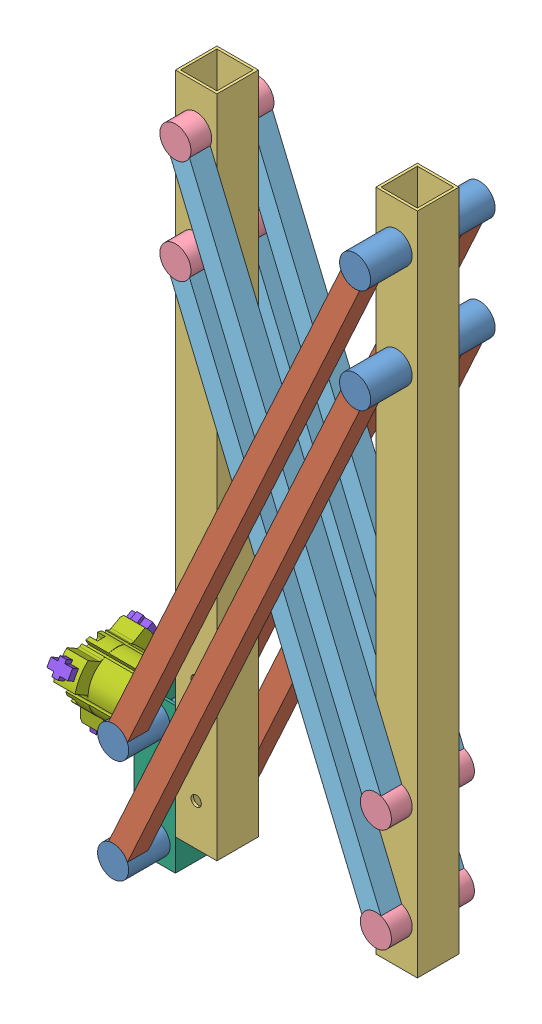
SolidWorks assembly Arm Assembly, configuration Down. Lengths in mm.
Overall size (424.42 852.13 156.64).
24 component instances, 8 part files, 47 mates.
Components (placement in the parent):
- End Long-1: End Long [Default] at (270.7162 -334.2521 -37.7204) x (-0.353555 0.935414 0) z (0 0 1)
- Link Long-1: Link Long [Default] at (-13.8532 -986.1623 13.0796) x (0.416361 0.909199 0) z (0.909199 -0.416361 0)
- Link Long-2: Link Long [Default] at (-13.8532 -986.1623 -113.9204) x (0.416361 0.909199 0) z (0.909199 -0.416361 0)
- End Long-2: End Long [Default] at (-25.4 -980.8746 -37.7204) x (0.851709 -0.524015 0) z (0 0 1)
- End Long-3: End Long [Default] at (-25.4 -853.8746 -37.7204) x (-0.966098 0.258174 0) z (0 0 1)
- Link Long-3: Link Long [Default] at (-13.8532 -859.1623 13.0796) x (0.416361 0.909199 0) z (0.909199 -0.416361 0)
- Link Long-4: Link Long [Default] at (-13.8532 -859.1623 -113.9204) x (0.416361 0.909199 0) z (0.909199 -0.416361 0)
- End Long-4: End Long [Default] at (270.7162 -207.2521 -37.7204) x (0.945044 0.326943 0) z (0 0 1)
- Post-2: Post [Default] at (270.7162 -156.4521 -37.7204) x (0 0 -1) z (-1 0 0)
- End Short-1: End Short [Default] at (25.4 -332.7517 -37.7204) x (0.945044 0.326943 0) z (0 0 1)
- End Short-2: End Short [Default] at (270.7162 -918.4521 -37.7204) x (0.945044 0.326943 0) z (0 0 1)
- Link Short-1: Link Short [Default] at (13.686 -337.658 -88.5204) x (0.386325 -0.922363 0) z (-0.922363 -0.386325 0)
- Link Short-2: Link Short [Default] at (13.686 -337.658 -12.3204) x (0.386325 -0.922363 0) z (-0.922363 -0.386325 0)
- Link Short-3: Link Short [Default] at (13.686 -210.658 -12.3204) x (0.386325 -0.922363 0) z (-0.922363 -0.386325 0)
- Link Short-4: Link Short [Default] at (13.686 -210.658 -88.5204) x (0.386325 -0.922363 0) z (-0.922363 -0.386325 0)
- End Short-3: End Short [Default] at (270.7162 -791.4521 -37.7204) x (0.945044 0.326943 0) z (0 0 1)
- End Short-4: End Short [Default] at (25.4 -205.7517 -37.7204) x (0.945044 0.326943 0) z (0 0 1)
- Post-4: Post [Default] at (25.4 -967.7517 -37.7204) x (0 0 -1) z (1 0 0)
- Post Short-1: Post Short [Default] at (-25.4 -1006.2746 -37.7204) x (0 0 -1) z (1 0 0)
- MHSL3-50D-1: MHSL3-50D [MHSL3-50D] at (-50.8 -863.4746 -37.7204) x (-1 0 0) z (0 -0.866025 0.5) size (77.5 98.66 113.92)
  - MHSL3-50D_MHSL-Body-1: MHSL3-50D_MHSL-Body [50] x (-1 0 0) z (0 0 -1) size (74.5 90.6 101.7)
  - MHSL3-50D_MHSL-Finger-1: MHSL3-50D_MHSL-Finger [50] at (61 -48 0) x (-1 0 0) z (0 0 1) size (26.2 24 20)
  - MHSL3-50D_MHSL-Finger-2: MHSL3-50D_MHSL-Finger [50] at (61 24 41.5692) x (-1 0 0) z (0 0.866025 -0.5) size (26.2 24 20)
  - MHSL3-50D_MHSL-Finger-3: MHSL3-50D_MHSL-Finger [50] at (61 24 -41.5692) x (-1 0 0) z (0 -0.866025 -0.5) size (26.2 24 20)
Mates (geometry in assembly coordinates):
- Concentric1: concentric anti-aligned: cylinder of End Long-1 through (270.7162 -334.2521 -113.9204) axis (0 0 -1) radius 19.05; cylinder of Link Long-1 through (270.7162 -334.2521 13.0796) axis (0 0 1) radius 19.05
- Coincident1: coincident aligned: plane of End Long-1 through (270.7162 -334.2521 38.4796) normal (0 0 1); plane of Link Long-1 through (282.2631 -339.5399 38.4796) normal (0 0 1)
- Concentric2: concentric anti-aligned: cylinder of End Long-1 through (270.7162 -334.2521 -113.9204) axis (0 0 -1) radius 19.05; cylinder of Link Long-2 through (270.7162 -334.2521 -113.9204) axis (0 0 1) radius 19.05
- Coincident2: coincident aligned: plane of End Long-1 through (252.8966 -340.9873 -113.9204) normal (0 0 -1); plane of Link Long-2 through (282.2631 -339.5399 -113.9204) normal (0 0 -1)
- Concentric3: concentric anti-aligned: cylinder of Link Long-1 through (-25.4 -980.8746 13.0796) axis (0 0 1) radius 19.05; cylinder of End Long-2 through (-25.4 -980.8746 -113.9204) axis (0 0 -1) radius 19.05
- Coincident3: coincident aligned: plane of Link Long-1 through (282.2631 -339.5399 38.4796) normal (0 0 1); plane of End Long-2 through (-25.4 -980.8746 38.4796) normal (0 0 1)
- Concentric4: concentric anti-aligned: cylinder of Link Long-4 through (270.7162 -207.2521 -113.9204) axis (0 0 1) radius 19.05; cylinder of End Long-4 through (270.7162 -207.2521 -113.9204) axis (0 0 -1) radius 19.05
- Concentric5: concentric anti-aligned: cylinder of End Long-3 through (-25.4 -853.8746 -113.9204) axis (0 0 -1) radius 19.05; cylinder of Link Long-3 through (-25.4 -853.8746 13.0796) axis (0 0 1) radius 19.05
- Concentric6: concentric anti-aligned: cylinder of Link Long-3 through (270.7162 -207.2521 13.0796) axis (0 0 1) radius 19.05; cylinder of End Long-4 through (270.7162 -207.2521 -113.9204) axis (0 0 -1) radius 19.05
- Coincident4: coincident aligned: plane of End Long-3 through (-25.4 -853.8746 38.4796) normal (0 0 1); plane of Link Long-3 through (282.2631 -212.5399 38.4796) normal (0 0 1)
- Coincident5: coincident aligned: plane of Link Long-4 through (282.2631 -212.5399 -113.9204) normal (0 0 -1); plane of End Long-4 through (264.488 -189.249 -113.9204) normal (0 0 -1)
- Coincident6: coincident aligned: plane of Link Long-3 through (282.2631 -212.5399 38.4796) normal (0 0 1); plane of End Long-4 through (270.7162 -207.2521 38.4796) normal (0 0 1)
- Concentric7: concentric anti-aligned: cylinder of End Long-1 through (270.7162 -334.2521 -113.9204) axis (0 0 -1) radius 6.35; circle of Post-2
- Concentric8: concentric anti-aligned: cylinder of End Long-4 through (270.7162 -207.2521 -113.9204) axis (0 0 -1) radius 6.35; circle of Post-2
- Coincident9: coincident aligned: plane of Link Long-1 through (282.2631 -339.5399 38.4796) normal (0 0 1); plane of Link Long-3 through (282.2631 -212.5399 38.4796) normal (0 0 1)
- Distance1: distance = 50.8 mm aligned: plane of End Long-4 through (270.7162 -207.2521 38.4796) normal (0 0 1); plane of Post-2 through (296.1162 -969.2521 -12.3204) normal (0 0 1)
- Concentric9: concentric anti-aligned: cylinder of Link Long-2 through (-25.4 -980.8746 -113.9204) axis (0 0 1) radius 19.05; cylinder of End Long-2 through (-25.4 -980.8746 -113.9204) axis (0 0 -1) radius 19.05
- Concentric10: concentric anti-aligned: cylinder of End Long-3 through (-25.4 -853.8746 -113.9204) axis (0 0 -1) radius 19.05; cylinder of Link Long-4 through (-25.4 -853.8746 -113.9204) axis (0 0 1) radius 19.05
- Concentric11: concentric anti-aligned: cylinder of End Short-2 through (270.7162 -918.4521 -88.5204) axis (0 0 -1) radius 19.05; cylinder of Link Short-2 through (270.7162 -918.4521 -12.3204) axis (0 0 1) radius 19.05
- Coincident11: coincident aligned: plane of End Short-2 through (270.7162 -918.4521 13.0796) normal (0 0 1); plane of Link Short-2 through (259.0022 -923.3584 13.0796) normal (0 0 1)
- Concentric12: concentric anti-aligned: cylinder of End Short-1 through (25.4 -332.7517 -88.5204) axis (0 0 -1) radius 19.05; cylinder of Link Short-2 through (25.4 -332.7517 -12.3204) axis (0 0 1) radius 19.05
- Coincident12: coincident aligned: plane of End Short-1 through (25.4 -332.7517 13.0796) normal (0 0 1); plane of Link Short-2 through (259.0022 -923.3584 13.0796) normal (0 0 1)
- Concentric13: concentric anti-aligned: cylinder of End Short-1 through (25.4 -332.7517 -88.5204) axis (0 0 -1) radius 19.05; cylinder of Link Short-1 through (25.4 -332.7517 -88.5204) axis (0 0 1) radius 19.05
- Coincident13: coincident aligned: plane of End Short-1 through (19.1717 -314.7486 -88.5204) normal (0 0 -1); plane of Link Short-1 through (259.0022 -923.3584 -88.5204) normal (0 0 -1)
- Concentric14: concentric anti-aligned: cylinder of End Short-2 through (270.7162 -918.4521 -88.5204) axis (0 0 -1) radius 19.05; cylinder of Link Short-1 through (270.7162 -918.4521 -88.5204) axis (0 0 1) radius 19.05
- Concentric15: concentric anti-aligned: cylinder of Link Short-3 through (25.4 -205.7517 -12.3204) axis (0 0 1) radius 19.05; cylinder of End Short-4 through (25.4 -205.7517 -88.5204) axis (0 0 -1) radius 19.05
- Concentric16: concentric anti-aligned: cylinder of Link Short-4 through (270.7162 -791.4521 -88.5204) axis (0 0 1) radius 19.05; cylinder of End Short-3 through (270.7162 -791.4521 -88.5204) axis (0 0 -1) radius 19.05
- Concentric17: concentric anti-aligned: cylinder of Link Short-4 through (25.4 -205.7517 -88.5204) axis (0 0 1) radius 19.05; cylinder of End Short-4 through (25.4 -205.7517 -88.5204) axis (0 0 -1) radius 19.05
- Concentric18: concentric anti-aligned: cylinder of Link Short-3 through (270.7162 -791.4521 -12.3204) axis (0 0 1) radius 19.05; cylinder of End Short-3 through (270.7162 -791.4521 -88.5204) axis (0 0 -1) radius 19.05
- Coincident14: coincident aligned: plane of Link Short-4 through (259.0022 -796.3584 -88.5204) normal (0 0 -1); plane of End Short-4 through (19.1717 -187.7486 -88.5204) normal (0 0 -1)
- Coincident15: coincident aligned: plane of Link Short-3 through (259.0022 -796.3584 13.0796) normal (0 0 1); plane of End Short-4 through (25.4 -205.7517 13.0796) normal (0 0 1)
- Coincident16: coincident aligned: plane of Link Short-3 through (259.0022 -796.3584 13.0796) normal (0 0 1); plane of End Short-3 through (270.7162 -791.4521 13.0796) normal (0 0 1)
- Concentric19: concentric anti-aligned: circle of Post-2; cylinder of End Short-3 through (270.7162 -791.4521 -88.5204) axis (0 0 -1) radius 6.35
- Coincident18: coincident aligned: plane of Link Short-2 through (259.0022 -923.3584 13.0796) normal (0 0 1); plane of Link Short-3 through (259.0022 -796.3584 13.0796) normal (0 0 1)
- Concentric20: concentric anti-aligned: circle of Post-2; cylinder of End Short-2 through (270.7162 -918.4521 -88.5204) axis (0 0 -1) radius 6.35
- Distance2: distance = 25.4 mm aligned: plane of End Short-3 through (270.7162 -791.4521 13.0796) normal (0 0 1); plane of Post-2 through (296.1162 -969.2521 -12.3204) normal (0 0 1)
- Concentric24: concentric anti-aligned: cylinder of End Short-4 through (25.4 -205.7517 -88.5204) axis (0 0 -1) radius 6.35; circle of Post-4
- Concentric25: concentric anti-aligned: cylinder of End Short-1 through (25.4 -332.7517 -88.5204) axis (0 0 -1) radius 6.35; circle of Post-4
- Distance5: distance = 25.4 mm aligned: plane of End Short-1 through (25.4 -332.7517 13.0796) normal (0 0 1); plane of Post-4 through (0 -154.9517 -12.3204) normal (0 0 1)
- Concentric26: concentric anti-aligned: cylinder of End Long-3 through (-25.4 -853.8746 -113.9204) axis (0 0 -1) radius 6.35; circle of Post Short-1
- Concentric27: concentric anti-aligned: cylinder of End Long-2 through (-25.4 -980.8746 -113.9204) axis (0 0 -1) radius 6.35; circle of Post Short-1
- Distance6: distance = 50.8 mm aligned: plane of Post Short-1 through (-50.8 -828.4746 -12.3204) normal (0 0 1); plane of End Long-2 through (-25.4 -980.8746 38.4796) normal (0 0 1)
- Coincident21: coincident anti-aligned: plane of Post Short-1 through (-50.8 -828.4746 -12.3204) normal (-1 0 0); plane of MHSL3-50D-1/MHSL3-50D_MHSL-Body-1 through (-50.8 -876.4746 -60.237) normal (1 0 0)
- Parallel1: parallel aligned: plane of Post Short-1 through (-50.8 -828.4746 -12.3204) normal (0 0 1); plane of MHSL3-50D-1/MHSL3-50D_MHSL-Body-1 through (-50.8 -912.9518 -21.7204) normal (0 0 1)
- Coincident25: coincident: moEndPointRef_w of Post Short-1; moEndPointRef_w of MHSL3-50D-1/MHSL3-50D_MHSL-Body-1
- Coincident26: coincident anti-aligned: plane of Post-4 through (0 -154.9517 -12.3204) normal (-1 0 0); plane of assembly through (0 0 0) normal (1 0 0)
- Coincident28: coincident anti-aligned: plane of Post-4 through (0 -154.9517 -12.3204) normal (-1 0 0); plane of Post Short-1 through (0 -828.4746 -12.3204) normal (1 0 0)
